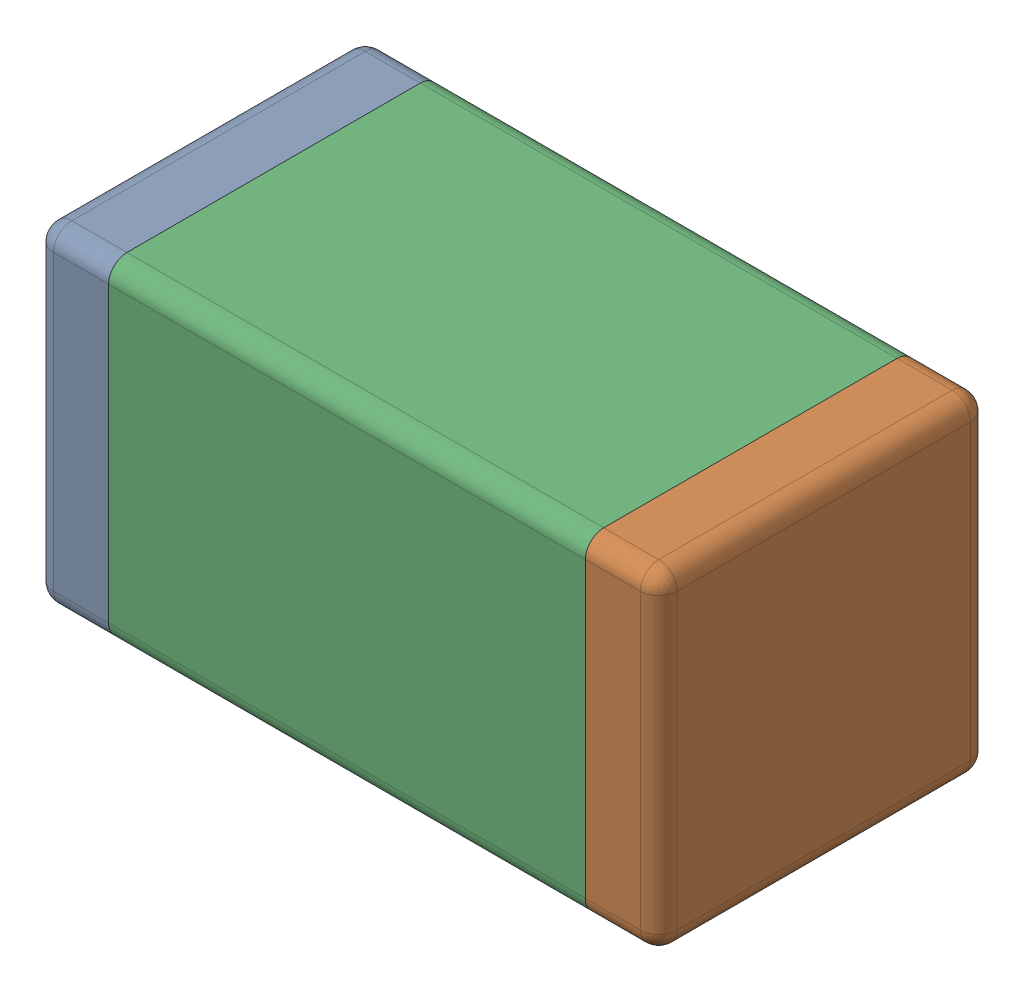
SolidWorks assembly 6689447584, configuration Default. Lengths in mm.
Overall size (1.7 0.9 0.9).
5 component instances, 3 part files, 0 mates.
Components (placement in the parent):
- Terminal_6-1: Terminal_6 [Default] at (-0.85 -0.45 0) size (1.7 0.9 0.9)
  - Open CASCADE STEP translator 6.8 6.1.1_2-1: Open CASCADE STEP translator 6.8 6.1.1_2 [Default] at origin size (0.2 0.9 0.9)
  - Open CASCADE STEP translator 6.8 6.1.2_2-1: Open CASCADE STEP translator 6.8 6.1.2_2 [Default] at origin size (0.2 0.9 0.9)
- Mid_Body_3-1: Mid_Body_3 [Default] at (-0.85 -0.45 0) size (1.3 0.9 0.9)
  - Open CASCADE STEP translator 6.8 6.2.1_2-1: Open CASCADE STEP translator 6.8 6.2.1_2 [Default] at origin size (1.3 0.9 0.9)
